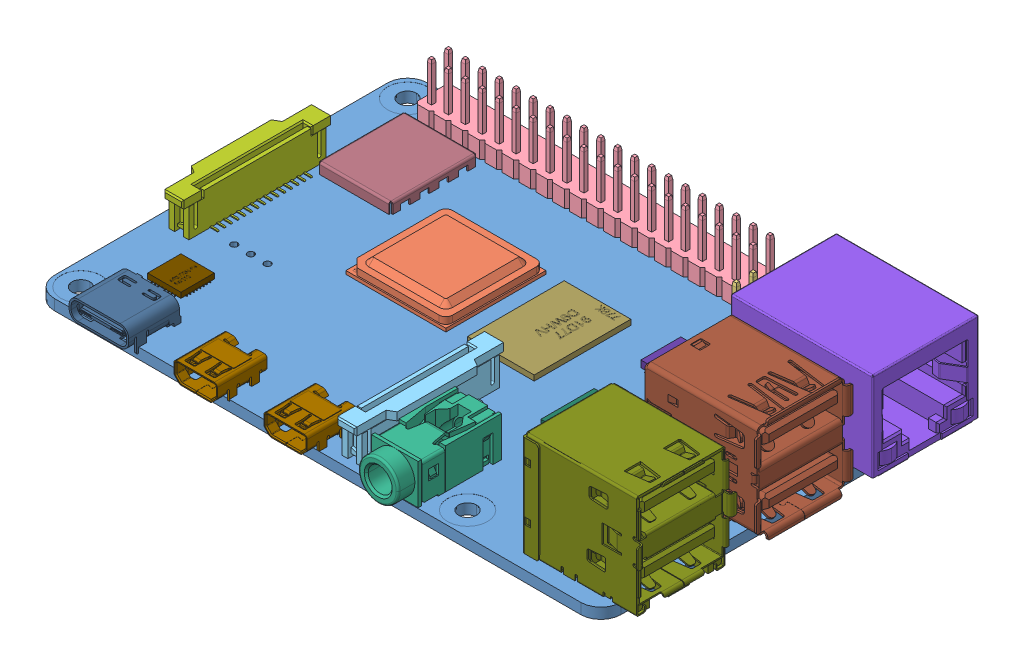
SolidWorks assembly Raspberry Pi 4 Model B, configuration Default. Lengths in mm.
Overall size (89 19.92 58.4).
19 component instances, 18 part files, 0 mates.
Components (placement in the parent):
- PCB, RPi4ModelB.STEP-1: PCB, RPi4ModelB.STEP [Default] at origin size (85 1.6 56)
- Broadcom BCM2711B0 CPU, RPi4ModelB.STEP-1: Broadcom BCM2711B0 CPU, RPi4ModelB.STEP [Default] at (-13.25 0.8 -4.5) size (15 2.3 15)
- 2.54 mm DUPONT MALE PIN HEADER, POE, 2X2, RPi4ModelB.STEP-1: 2.54 mm DUPONT MALE PIN HEADER, POE, 2X2, RPi4ModelB.STEP [Default] at (19 0.8 -18.36) size (5.08 11.3 5.08)
- 2.54 mm DUPONT MALE PIN HEADER, IO, 2X20, RPi4ModelB.STEP-1: 2.54 mm DUPONT MALE PIN HEADER, IO, 2X20, RPi4ModelB.STEP [Default] at (-10 0.8 -24.5) size (50.8 11.3 5.08)
- Camera Connector, RPi4ModelB.STEP-1: Camera Connector, RPi4ModelB.STEP [Default] at (4 0.8 16.5) x (0 0 -1) z (1 0 0) size (22.4 5.68 5.07)
- Microphone Plug, RPi4ModelB.STEP-1: Microphone Plug, RPi4ModelB.STEP [Default] at (11.5 0.8 21.65) size (7.23 7.55 15)
- Display Connector, RPi4ModelB.STEP-1: Display Connector, RPi4ModelB.STEP [Default] at (-38.5 0.8 0) x (0 0 1) z (-1 0 0) size (22.4 5.68 5.07)
- Gigabit Ethernet Port, RPi4ModelB.STEP-1: Gigabit Ethernet Port, RPi4ModelB.STEP [Default] at (45.5 7.55 -17.75) x (0 0 -1) z (1 0 0) size (16.33 17.24 21.6)
- Female Micro HDMI Connector, RPi4ModelB.STEP-1: Female Micro HDMI Connector, RPi4ModelB.STEP [Default] at (-3 0.8 27.3875) size (6.5 3.51 7.5)
- Female Micro HDMI Connector, RPi4ModelB.STEP-2: Female Micro HDMI Connector, RPi4ModelB.STEP [Default] at (-16.5 0.8 27.3875) size (6.5 3.51 7.5)
- Female USB Type C Connector, RPi4ModelB.STEP-1: Female USB Type C Connector, RPi4ModelB.STEP [Default] at (-31.3 0.8 26.5419) size (8.94 3.96 7.9)
- 2X USB3.0 PORTS, RPi4ModelB.STEP-1: 2X USB3.0 PORTS, RPi4ModelB.STEP [Default] at (37.07 0.8 1) size (17.48 19.42 15.69)
- 91D77 D9WHV 778K, 4 GB LPDDR4 SDRAM, RPi4ModelB.STEP-1: 91D77 D9WHV 778K, 4 GB LPDDR4 SDRAM, RPi4ModelB.STEP [Default] at (2.25 0.8 -4.5) size (10 0.8 14.5)
- Cypress CYW43455 Wireless Module Cover, RPi4ModelB.STEP-1: Cypress CYW43455 Wireless Module Cover, RPi4ModelB.STEP [Default] at (-30.5 0.8 -14.5) size (11 1.6 13)
- SD Card Slot, RPi4ModelB.STEP-1: SD Card Slot, RPi4ModelB.STEP [Default] at (-35.3 -0.8 0) x (0 0 -1) z (-1 0 0) size (11.95 1.45 11.4)
- VIA VL805 PCIe USB 3.0 controller, RPi4ModelB.STEP-1: VIA VL805 PCIe USB 3.0 controller, RPi4ModelB.STEP [Default] at (17.5 0.8 4) size (8.8 0.8 8.8)
- 2X USB2.0 PORTS, RPi4ModelB.STEP-1: 2X USB2.0 PORTS, RPi4ModelB.STEP [Default] at (37.065 0.65 19) size (17.87 19.17 15.35)
- Broadcom BCM54213PE Gigabit Ethernet Transceiver, RPi4ModelB.STEP-1: Broadcom BCM54213PE Gigabit Ethernet Transceiver, RPi4ModelB.STEP [Default] at (16.5 0.8 -10) size (6.8 1 6.8)
- MxL7704 Universal PMIC, RPi4ModelB.STEP-1: MxL7704 Universal PMIC, RPi4ModelB.STEP [Default] at (-32.5 0.8 16) size (5.4 0.8 5.4)
